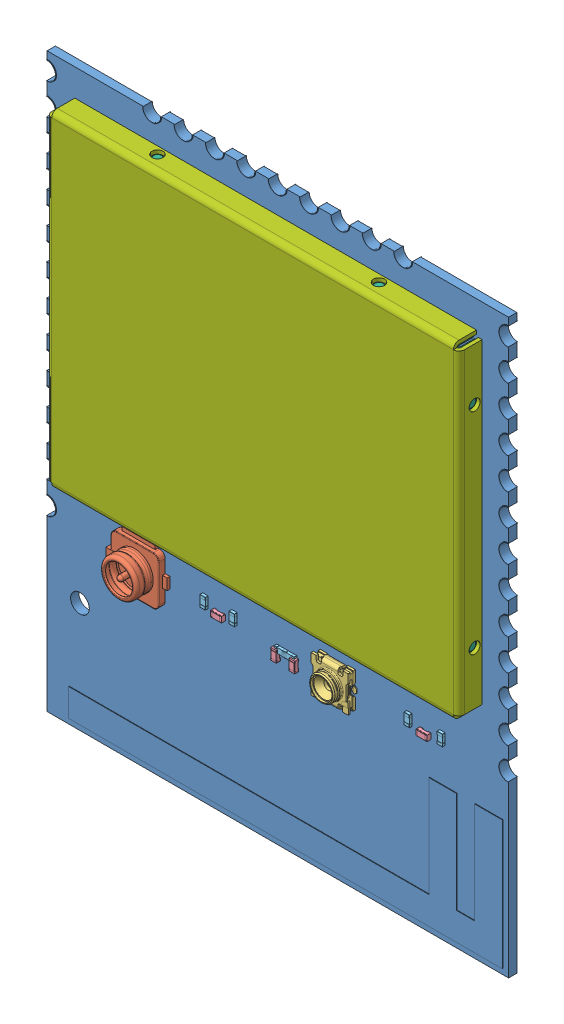
SolidWorks assembly imp002, configuration Default. Lengths in mm.
Overall size (25 31 2.9).
15 component instances, 7 part files, 0 mates.
Components (placement in the parent):
- shadow_pcb-1: shadow_pcb [Default] at origin size (25 31 0.51)
- U_FL_CONN-1: U_FL_CONN [Default] at (5.1048 9.3726 0.405) x (0 1 0) z (0 0 -1) size (3 3.1 1.27)
- SWG-VE-1: SWG-VE [Default] at (15.7504 9.3726 -7.2943) x (-1 0 0) z (0 0 1) size (3.12 3.83 2.9)
- RES0603___ _________-1: RES0603___ _________ [Default] at (12.4841 8.9916 0.4) x (0 1 0) z (0 0 1) size (0.6 0.3 0.23)
- RES0603___ _________-2: RES0603___ _________ [Default] at (13.4823 8.9891 0.4) x (0 1 0) z (0 0 1) size (0.6 0.3 0.23)
- RES0603___ _________-3: RES0603___ _________ [Default] at (9.3624 9.2405 0.4) size (0.6 0.3 0.23)
- RES0603___ _________-4: RES0603___ _________ [Default] at (20.5029 9.2431 0.4) x (-1 0 0) z (0 0 1) size (0.6 0.3 0.23)
- CAPC0603-1: CAPC0603 [Default] at (10.1473 9.4894 0.4) x (0 -1 0) z (0 0 1) size (0.6 0.3 0.3)
- CAPC0603-2: CAPC0603 [Default] at (8.5725 9.4844 0.4) x (0 -1 0) z (0 0 1) size (0.6 0.3 0.3)
- CAPC0603-3: CAPC0603 [Default] at (12.7325 9.2405 0.4) x (-1 0 0) z (0 0 1) size (0.6 0.3 0.3)
- CAPC0603-4: CAPC0603 [Default] at (19.6245 9.492 0.4) x (0 -1 0) z (0 0 1) size (0.6 0.3 0.3)
- CAPC0603-5: CAPC0603 [Default] at (21.418 9.492 0.4) x (0 -1 0) z (0 0 1) size (0.6 0.3 0.3)
- CAPC0603-6: CAPC0603 [Default] at (13.2304 9.2405 0.4) x (-1 0 0) z (0 0 1) size (0.6 0.3 0.3)
- shadow_shield_frame-1: shadow_shield_frame [Default] at (0 0 0.4) size (22.07 17.43 1.3)
- shadow_shield_lid-1: shadow_shield_lid [Default] at origin size (22.36 17.72 1.25)
